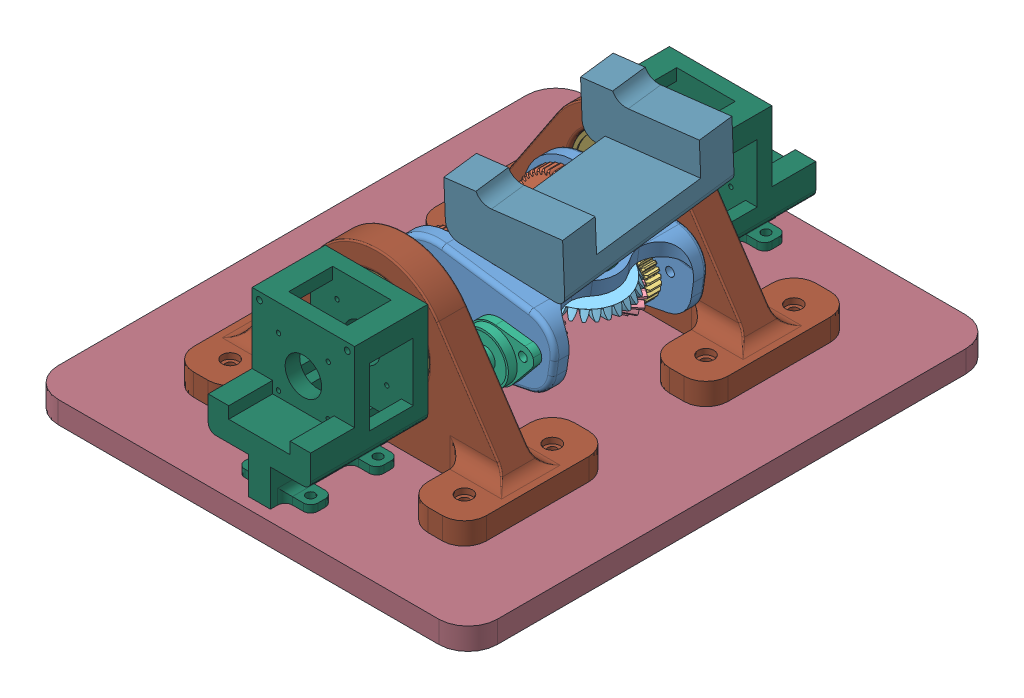
SolidWorks assembly ASSEMBLY Full Design 6th Attempt - Motor Holder, configuration Default. Lengths in mm.
Overall size (300 171.25 360).
32 component instances, 15 part files, 78 mates.
Components (placement in the parent):
- Main Case-1: Main Case [Default] at (-6.6195 108.5231 36.8157) x (0.989686 -0.143255 0) z (0 0 1) size (115 70 185)
- Secondary Big Spur Gear-1: Secondary Big Spur Gear [Default] at (-6.6195 108.5231 51.8157) x (0.357057 0.934082 0) z (0 0 1) size (62.4 62.32 10)
- Secondary Big Spur Gear-2: Secondary Big Spur Gear [Default] at (-6.6195 108.5231 126.8157) x (-0.319318 0.947648 0) z (0 0 1) size (62.4 62.32 10)
- Main Spur Gear - Copy-1: Main Spur Gear - Copy [Default] at (37.9163 102.0767 126.8157) x (-0.43283 0.901476 0) z (0 0 1) size (32.38 32.33 10)
- Main Spur Gear - Copy-2: Main Spur Gear - Copy [Default] at (37.9163 102.0767 51.8157) x (-0.929585 0.368609 0) z (0 0 1) size (32.38 32.33 10)
- Secondary Bevel Gear-1: Secondary Bevel Gear [Default] at (37.9163 102.0767 59.4378) x (0.929585 -0.368609 0) z (-0.368609 -0.929585 0) size (38.4 11.9 38.26)
- Secondary Bevel Gear-2: Secondary Bevel Gear [Default] at (37.9163 102.0767 119.1936) x (-0.43283 0.901476 0) z (-0.901476 -0.43283 0) size (38.4 11.9 38.26)
- Secondary Main Bevel Gear-1: Secondary Main Bevel Gear [Default] at (40.3976 119.2185 89.3157) x (-0.989538 0.143233 -0.017312) z (-0.017134 0.00248 0.99985) size (61.9 10.12 62)
- Main Slewing Bearing-1: Main Slewing Bearing [Default] at (42.9302 136.7157 89.3157) x (0 0 -1) z (0.989686 -0.143255 0) size (60 15.5 36)
- Secondary Gear Shaft-1: Secondary Gear Shaft [Default] at (46.6696 162.5492 89.3157) x (0.989538 -0.143233 0.017312) z (0.017134 -0.00248 -0.99985) size (10 46 10)
- Secondary Gear Shaft Horizontal-1: Secondary Gear Shaft Horizontal [Default] at (37.9163 102.0767 158.285) x (0.43283 -0.901476 0) z (0.901476 0.43283 0) size (10 46 10)
- Secondary Gear Shaft Horizontal-3: Secondary Gear Shaft Horizontal [Default] at (37.9163 102.0767 20.3464) x (-0.929585 0.368609 0) z (0.368609 0.929585 0) size (10 46 10)
- Main Slewing Bearing-2: Main Slewing Bearing [Default] at (37.9163 102.0767 36.8157) x (0.92872 0.370781 0) z (-0.370781 0.92872 0) size (60 15.5 36)
- Main Slewing Bearing-3: Main Slewing Bearing [Default] at (37.9163 102.0767 141.8157) x (0.92872 0.370781 0) z (0.370781 -0.92872 0) size (60 15.5 36)
- Main Bearing-1: Main Bearing [Default] at (-6.6195 108.5231 136.8157) size (25 25 10)
- Main Bearing-2: Main Bearing [Default] at (-6.6195 108.5231 41.8157) size (25 25 10)
- Secondary Gear Shaft Horizontal Back-1: Secondary Gear Shaft Horizontal Back [Default] at (-6.6195 108.5231 -23.1843) x (0.357057 0.934082 0) z (0.934082 -0.357057 0) size (10 80 10)
- Secondary Gear Shaft Horizontal Back-2: Secondary Gear Shaft Horizontal Back [Default] at (-6.6195 108.5231 201.8157) x (0.319318 -0.947648 0) z (0.947648 0.319318 0) size (10 80 10)
- Main Bearing-3: Main Bearing [Default] at (-6.6195 108.5231 176.8157) size (25 25 10)
- Main Bearing-4: Main Bearing [Default] at (-6.6195 108.5231 1.8157) x (0.957621 -0.288033 0) z (0 0 1) size (25 25 10)
- Main Holder-1: Main Holder [Default] at (-6.6195 108.5231 171.8157) size (200 110 100)
- Main Holder-2: Main Holder [Default] at (-6.6195 108.5231 6.8157) size (200 110 100)
- Main Bearing Big-1: Main Bearing Big [Default] at (-6.6195 108.5231 171.8157) size (70 70 15)
- Main Bearing Big-2: Main Bearing Big [Default] at (-6.6195 108.5231 6.8157) size (70 70 15)
- Bottom Plate-1: Bottom Plate [Default] at (-6.6195 33.5231 89.3157) x (0 0 1) z (-1 0 0) size (360 15 300)
- Ham Duong-1: Ham Duong [Default] at (9.1871 201.8442 93.8718) x (-0.9942 -0.025249 0.10454) z (-0.104942 0.01519 -0.994362) size (73.61 54.09 130)
- Main Motor Holder-1: Main Motor Holder [Default] at (-6.6195 108.5231 221.8157) size (70 95 80)
- Main Motor Holder-2: Main Motor Holder [Default] at (-6.6195 108.5231 -43.1843) x (-1 0 0) z (0 0 -1) size (70 95 80)
- Main Bearing-5: Main Bearing [Default] at (-6.6195 108.5231 -8.1843) size (25 25 10)
- Main Bearing-6: Main Bearing [Default] at (-6.6195 108.5231 186.8157) size (25 25 10) (hidden)
- Main Bearing-7: Main Bearing [Default] at (-6.6195 108.5231 226.8157) size (25 25 10) (hidden)
- Main Bearing-8: Main Bearing [Default] at (-6.6195 108.5231 -48.1843) size (25 25 10)
Mates (geometry in assembly coordinates):
- Concentric1: concentric aligned: cylinder of Main Case-1 through (-6.6195 108.5231 131.8157) axis (0 0 1) radius 12.5; cylinder of Secondary Big Spur Gear-2 through (-6.6195 108.5231 121.8157) axis (0 0 1) radius 5
- Coincident1: coincident anti-aligned: plane of Main Case-1 through (-6.6195 108.5231 131.8157) normal (0 0 -1); plane of Secondary Big Spur Gear-2 through (-6.6195 108.5231 131.8157) normal (0 0 1)
- Concentric2: concentric anti-aligned: cylinder of Main Case-1 through (-6.6195 108.5231 46.8157) axis (0 0 -1) radius 12.5; cylinder of Secondary Big Spur Gear-1 through (-6.6195 108.5231 46.8157) axis (0 0 1) radius 5
- Coincident2: coincident anti-aligned: plane of Main Case-1 through (-6.6195 108.5231 46.8157) normal (0 0 1); plane of Secondary Big Spur Gear-1 through (-6.6195 108.5231 46.8157) normal (0 0 -1)
- Concentric3: concentric anti-aligned: cylinder of Main Case-1 through (37.9163 102.0767 46.8157) axis (0 0 -1) radius 5; cylinder of Main Spur Gear - Copy-2 through (37.9163 102.0767 46.8157) axis (0 0 1) radius 5
- Coincident3: coincident anti-aligned: plane of Main Case-1 through (-6.6195 108.5231 46.8157) normal (0 0 1); plane of Main Spur Gear - Copy-2 through (37.9163 102.0767 46.8157) normal (0 0 -1)
- GearMate1: gear = 60 : 30 mm: circle of Main Spur Gear - Copy-2; circle of Secondary Big Spur Gear-1
- Concentric5: concentric aligned: cylinder of Main Case-1 through (37.9163 102.0767 131.8157) axis (0 0 1) radius 5; cylinder of Main Spur Gear - Copy-1 through (37.9163 102.0767 121.8157) axis (0 0 1) radius 5
- Coincident4: coincident anti-aligned: plane of Main Case-1 through (-6.6195 108.5231 131.8157) normal (0 0 -1); plane of Main Spur Gear - Copy-1 through (37.9163 102.0767 131.8157) normal (0 0 1)
- GearMate2: gear = 60 : 30 mm: circle of Main Spur Gear - Copy-1; circle of Secondary Big Spur Gear-2
- Concentric7: concentric aligned: cylinder of Main Case-1 through (37.9163 102.0767 46.8157) axis (0 0 -1) radius 5; cylinder of Secondary Bevel Gear-1 through (37.9163 102.0767 68.8963) axis (0 0 -1) radius 5
- Coincident5: coincident aligned: plane of Main Spur Gear - Copy-2 through (37.1952 94.8324 46.8157) normal (0.368609 0.929585 0); plane of Secondary Bevel Gear-1 through (33.4769 96.3068 68.8963) normal (0.368609 0.929585 0)
- Concentric8: concentric aligned: cylinder of Main Spur Gear - Copy-1 through (37.9163 102.0767 121.8157) axis (0 0 1) radius 5; cylinder of Secondary Bevel Gear-2 through (37.9163 102.0767 109.7351) axis (0 0 1) radius 5
- Coincident6: coincident aligned: plane of Main Spur Gear - Copy-1 through (32.4717 97.2439 121.8157) normal (0.901476 0.43283 0); plane of Secondary Bevel Gear-2 through (32.4717 97.2439 109.7351) normal (0.901476 0.43283 0)
- Concentric9: concentric aligned: cylinder of Main Case-1 through (32.9024 67.4377 89.3157) axis (0.143255 0.989686 0) radius 5; cylinder of Secondary Main Bevel Gear-1 through (39.5059 113.0582 89.3157) axis (0.143255 0.989686 0) radius 5
- Coincident7: coincident: point of Secondary Bevel Gear-1; point of Secondary Main Bevel Gear-1
- Coincident8: coincident: line of Secondary Bevel Gear-2 through (37.9163 102.0767 89.3157) axis (0.216415 -0.450738 0.866025)
- GearMate3: gear = 34.5 : 60 mm: circle of Secondary Main Bevel Gear-1; circle of Secondary Bevel Gear-1
- GearMate4: gear = 60 : 34.5 mm: circle of Secondary Bevel Gear-2; circle of Secondary Main Bevel Gear-1
- Concentric11: concentric aligned: cylinder of Main Case-1 through (32.9024 67.4377 89.3157) axis (0.143255 0.989686 0) radius 5; cylinder of Main Slewing Bearing-1 through (42.9302 136.7157 89.3157) axis (0.143255 0.989686 0) radius 5
- Concentric12: concentric anti-aligned: cylinder of Main Case-1 through (42.9302 136.7157 66.8157) axis (0.143255 0.989686 0) radius 3; cylinder of Main Slewing Bearing-1 through (43.7181 142.1589 66.8157) axis (-0.143255 -0.989686 0) radius 3
- Coincident9: coincident anti-aligned: plane of Main Case-1 through (-1.6056 143.1621 46.8157) normal (0.143255 0.989686 0); plane of Main Slewing Bearing-1 through (42.9302 136.7157 89.3157) normal (-0.143255 -0.989686 0)
- Concentric13: concentric aligned: cylinder of Main Slewing Bearing-1 through (42.9302 136.7157 89.3157) axis (0.143255 0.989686 0) radius 5; cylinder of Secondary Gear Shaft-1 through (40.0799 117.0237 89.3157) axis (0.143255 0.989686 0) radius 5
- Coincident10: coincident aligned: plane of Secondary Main Bevel Gear-1 through (59.6258 114.1945 89.6577) normal (-0.143255 -0.989686 0); plane of Secondary Gear Shaft-1 through (40.0799 117.0237 89.3157) normal (-0.143255 -0.989686 0)
- Coincident11: coincident aligned: plane of Secondary Main Bevel Gear-1 through (41.4064 112.7831 93.9322) normal (-0.989538 0.143233 -0.017312); plane of Secondary Gear Shaft-1 through (43.4401 126.6415 92.3499) normal (-0.989538 0.143233 -0.017312)
- Concentric14: concentric aligned: cylinder of Secondary Bevel Gear-1 through (37.9163 102.0767 68.8963) axis (0 0 -1) radius 5; cylinder of Secondary Gear Shaft Horizontal-3 through (37.9163 102.0767 66.3464) axis (0 0 -1) radius 5
- Coincident12: coincident aligned: plane of Secondary Bevel Gear-1 through (29.3082 105.4901 66.3464) normal (0 0 1); plane of Secondary Gear Shaft Horizontal-3 through (37.9163 102.0767 66.3464) normal (0 0 1)
- Coincident15: coincident aligned: plane of Secondary Bevel Gear-1 through (34.368 98.554 68.8963) normal (0.929585 -0.368609 0); plane of Secondary Gear Shaft Horizontal-3 through (34.9513 100.0251 56.3464) normal (0.929585 -0.368609 0)
- Concentric15: concentric aligned: cylinder of Secondary Bevel Gear-2 through (37.9163 102.0767 109.7351) axis (0 0 1) radius 5; cylinder of Secondary Gear Shaft Horizontal-1 through (37.9163 102.0767 112.285) axis (0 0 1) radius 5
- Coincident16: coincident aligned: plane of Secondary Bevel Gear-2 through (41.9244 93.7288 112.285) normal (0 0 -1); plane of Secondary Gear Shaft Horizontal-1 through (37.9163 102.0767 112.285) normal (0 0 -1)
- Coincident17: coincident aligned: plane of Secondary Bevel Gear-2 through (34.6509 98.2902 109.7351) normal (-0.43283 0.901476 0); plane of Secondary Gear Shaft Horizontal-1 through (36.0776 98.9752 122.285) normal (-0.43283 0.901476 0)
- Concentric16: concentric aligned: cylinder of Secondary Gear Shaft Horizontal-3 through (37.9163 102.0767 66.3464) axis (0 0 -1) radius 5; cylinder of Main Slewing Bearing-2 through (37.9163 102.0767 36.8157) axis (0 0 -1) radius 5
- Coincident18: coincident anti-aligned: plane of Main Case-1 through (-6.6195 108.5231 36.8157) normal (0 0 -1); plane of Main Slewing Bearing-2 through (37.9163 102.0767 36.8157) normal (0 0 1)
- Concentric17: concentric anti-aligned: cylinder of Main Case-1 through (58.8125 110.4192 141.8157) axis (0 0 -1) radius 3; cylinder of Main Slewing Bearing-2 through (58.8125 110.4192 31.3157) axis (0 0 1) radius 3
- Concentric18: concentric aligned: cylinder of Secondary Gear Shaft Horizontal-1 through (37.9163 102.0767 112.285) axis (0 0 1) radius 5; cylinder of Main Slewing Bearing-3 through (37.9163 102.0767 141.8157) axis (0 0 1) radius 5
- Concentric19: concentric aligned: cylinder of Main Case-1 through (58.8125 110.4192 141.8157) axis (0 0 -1) radius 3; cylinder of Main Slewing Bearing-3 through (58.8125 110.4192 147.3157) axis (0 0 -1) radius 3
- Coincident19: coincident anti-aligned: plane of Main Case-1 through (-6.6195 108.5231 141.8157) normal (0 0 1); plane of Main Slewing Bearing-3 through (37.9163 102.0767 141.8157) normal (0 0 -1)
- Concentric20: concentric anti-aligned: cylinder of Main Case-1 through (-6.6195 108.5231 131.8157) axis (0 0 1) radius 12.5; cylinder of Main Bearing-1 through (-6.6195 108.5231 141.8157) axis (0 0 -1) radius 12.5
- Coincident20: coincident aligned: plane of Main Case-1 through (-6.6195 108.5231 141.8157) normal (0 0 1); plane of Main Bearing-1 through (-6.6195 108.5231 141.8157) normal (0 0 1)
- Concentric21: concentric aligned: cylinder of Main Case-1 through (-6.6195 108.5231 46.8157) axis (0 0 -1) radius 12.5; cylinder of Main Bearing-2 through (-6.6195 108.5231 46.8157) axis (0 0 -1) radius 5
- Coincident21: coincident aligned: plane of Main Case-1 through (-6.6195 108.5231 36.8157) normal (0 0 -1); plane of Main Bearing-2 through (-6.6195 108.5231 36.8157) normal (0 0 -1)
- Concentric22: concentric aligned: cylinder of Main Bearing-2 through (-6.6195 108.5231 46.8157) axis (0 0 -1) radius 5; cylinder of Secondary Gear Shaft Horizontal Back-1 through (-6.6195 108.5231 56.8157) axis (0 0 -1) radius 5
- Coincident22: coincident aligned: plane of Secondary Big Spur Gear-1 through (-6.6195 108.5231 56.8157) normal (0 0 1); plane of Secondary Gear Shaft Horizontal Back-1 through (-6.6195 108.5231 56.8157) normal (0 0 1)
- Coincident23: coincident aligned: plane of Secondary Big Spur Gear-1 through (-11.6141 108.2912 46.8157) normal (0.357057 0.934082 0); plane of Secondary Gear Shaft Horizontal Back-1 through (-10.1359 107.7261 46.8157) normal (0.357057 0.934082 0)
- Concentric23: concentric anti-aligned: cylinder of Main Bearing-1 through (-6.6195 108.5231 141.8157) axis (0 0 -1) radius 5; cylinder of Secondary Gear Shaft Horizontal Back-2 through (-6.6195 108.5231 121.8157) axis (0 0 1) radius 5
- Coincident24: coincident aligned: plane of Secondary Big Spur Gear-2 through (-6.6195 108.5231 121.8157) normal (0 0 -1); plane of Secondary Gear Shaft Horizontal Back-2 through (-6.6195 108.5231 121.8157) normal (0 0 -1)
- Coincident25: coincident aligned: plane of Secondary Big Spur Gear-2 through (-10.3236 105.1645 121.8157) normal (-0.319318 0.947648 0); plane of Secondary Gear Shaft Horizontal Back-2 through (-8.8238 105.6699 131.8157) normal (-0.319318 0.947648 0)
- Concentric24: concentric anti-aligned: cylinder of Main Case-1 through (-6.6195 108.5231 131.8157) axis (0 0 1) radius 12.5; cylinder of Main Bearing-3 through (-6.6195 108.5231 181.8157) axis (0 0 -1) radius 12.5
- Coincident26: coincident aligned: plane of Main Case-1 through (-6.6195 108.5231 181.8157) normal (0 0 1); plane of Main Bearing-3 through (-6.6195 108.5231 181.8157) normal (0 0 1)
- Concentric25: concentric aligned: cylinder of Main Case-1 through (-6.6195 108.5231 46.8157) axis (0 0 -1) radius 12.5; cylinder of Main Bearing-4 through (-6.6195 108.5231 6.8157) axis (0 0 -1) radius 12.5
- Coincident27: coincident aligned: plane of Main Case-1 through (-6.6195 108.5231 -3.1843) normal (0 0 -1); plane of Main Bearing-4 through (-6.6195 108.5231 -3.1843) normal (0 0 -1)
- Concentric26: concentric aligned: cylinder of Main Holder-1 through (-6.6195 108.5231 221.8157) axis (0 0 -1) radius 35; cylinder of Main Bearing Big-1 through (-6.6195 108.5231 179.3157) axis (0 0 -1) radius 35
- Coincident28: coincident aligned: plane of Main Holder-1 through (-6.6195 108.5231 171.8157) normal (0 0 1); plane of Main Bearing Big-1 through (-6.6195 108.5231 171.8157) normal (0 0 1)
- Coincident29: coincident aligned: plane of Main Holder-2 through (-6.6195 108.5231 6.8157) normal (0 0 1); plane of Main Bearing Big-2 through (-6.6195 108.5231 6.8157) normal (0 0 1)
- Concentric27: concentric aligned: cylinder of Main Holder-2 through (-6.6195 108.5231 56.8157) axis (0 0 -1) radius 35; cylinder of Main Bearing Big-2 through (-6.6195 108.5231 14.3157) axis (0 0 -1) radius 35
- Concentric28: concentric aligned: cylinder of Main Case-1 through (-6.6195 108.5231 181.8157) axis (0 0 -1) radius 20; cylinder of Main Bearing Big-1 through (-6.6195 108.5231 179.3157) axis (0 0 -1) radius 20
- Concentric29: concentric anti-aligned: cylinder of Main Case-1 through (-6.6195 108.5231 -3.1843) axis (0 0 1) radius 20; cylinder of Main Bearing Big-2 through (-6.6195 108.5231 14.3157) axis (0 0 -1) radius 20
- Coincident30: coincident aligned: plane of Main Case-1 through (-6.6195 108.5231 181.8157) normal (0 0 1); plane of Main Holder-1 through (-6.6195 108.5231 181.8157) normal (0 0 1)
- Coincident31: coincident aligned: plane of Main Case-1 through (-6.6195 108.5231 -3.1843) normal (0 0 -1); plane of Main Holder-2 through (-6.6195 108.5231 -3.1843) normal (0 0 -1)
- Coincident32: coincident anti-aligned: plane of Main Holder-2 through (-106.6195 48.5231 16.8157) normal (0 -1 0); plane of Bottom Plate-1 through (-6.6195 48.5231 89.3157) normal (0 1 0)
- Concentric33: concentric aligned: cylinder of Secondary Gear Shaft-1 through (40.0799 117.0237 89.3157) axis (0.143255 0.989686 0) radius 5; cylinder of Ham Duong-1 through (44.9505 150.673 89.3157) axis (0.143255 0.989686 0) radius 5
- Coincident33: coincident anti-aligned: plane of Secondary Gear Shaft-1 through (46.6696 162.5492 89.3157) normal (0.143255 0.989686 0); plane of Ham Duong-1 through (70.8182 159.0538 21.3452) normal (-0.143255 -0.989686 0)
- Concentric34: concentric anti-aligned: cylinder of Secondary Gear Shaft Horizontal Back-2 through (-6.6195 108.5231 121.8157) axis (0 0 1) radius 5; cylinder of Main Motor Holder-1 through (-6.6195 108.5231 231.8157) axis (0 0 -1) radius 12.5
- Coincident34: coincident anti-aligned: plane of Main Holder-1 through (-6.6195 108.5231 181.8157) normal (0 0 1); plane of Main Motor Holder-1 through (-6.6195 108.5231 181.8157) normal (0 0 -1)
- Coincident35: coincident anti-aligned: plane of Bottom Plate-1 through (-6.6195 48.5231 89.3157) normal (0 1 0); plane of Main Motor Holder-1 through (-6.6195 48.5231 221.8157) normal (0 -1 0)
- Coincident36: coincident anti-aligned: plane of Bottom Plate-1 through (-6.6195 48.5231 89.3157) normal (0 1 0); plane of Main Motor Holder-2 through (-6.6195 48.5231 -43.1843) normal (0 -1 0)
- Coincident37: coincident anti-aligned: plane of Main Holder-2 through (-6.6195 108.5231 -3.1843) normal (0 0 -1); plane of Main Motor Holder-2 through (-6.6195 108.5231 -3.1843) normal (0 0 1)
- Concentric35: concentric anti-aligned: cylinder of Secondary Gear Shaft Horizontal Back-1 through (-6.6195 108.5231 56.8157) axis (0 0 -1) radius 5; cylinder of Main Motor Holder-2 through (-6.6195 108.5231 -53.1843) axis (0 0 1) radius 12.5
- Concentric37: concentric aligned: cylinder of Secondary Gear Shaft Horizontal Back-1 through (-6.6195 108.5231 56.8157) axis (0 0 -1) radius 5; cylinder of Main Bearing-5 through (-6.6195 108.5231 -3.1843) axis (0 0 -1) radius 12.5
- Coincident38: coincident aligned: plane of Main Motor Holder-2 through (-6.6195 108.5231 -13.1843) normal (0 0 -1); plane of Main Bearing-5 through (-6.6195 108.5231 -13.1843) normal (0 0 -1)
- Concentric39: concentric anti-aligned: cylinder of Main Motor Holder-2 through (-6.6195 108.5231 -53.1843) axis (0 0 1) radius 12.5; cylinder of Main Bearing-8 through (-6.6195 108.5231 -43.1843) axis (0 0 -1) radius 12.5
- Coincident39: coincident aligned: plane of Main Motor Holder-2 through (-6.6195 108.5231 -53.1843) normal (0 0 -1); plane of Main Bearing-8 through (-6.6195 108.5231 -53.1843) normal (0 0 -1)
- Concentric40: concentric anti-aligned: cylinder of Main Motor Holder-1 through (-6.6195 108.5231 181.8157) axis (0 0 1) radius 12.5; cylinder of Main Bearing-6 through (-6.6195 108.5231 191.8157) axis (0 0 -1) radius 12.5
- Coincident40: coincident aligned: plane of Main Motor Holder-1 through (-6.6195 108.5231 191.8157) normal (0 0 1); plane of Main Bearing-6 through (-6.6195 108.5231 191.8157) normal (0 0 1)
- Concentric41: concentric aligned: cylinder of Main Motor Holder-1 through (-6.6195 108.5231 231.8157) axis (0 0 -1) radius 12.5; cylinder of Main Bearing-7 through (-6.6195 108.5231 231.8157) axis (0 0 -1) radius 5
- Coincident41: coincident aligned: plane of Main Motor Holder-1 through (-6.6195 108.5231 231.8157) normal (0 0 1); plane of Main Bearing-7 through (-6.6195 108.5231 231.8157) normal (0 0 1)
- Concentric42: concentric aligned: cylinder of Main Holder-2 through (73.3805 63.5231 -23.1843) axis (0 1 0) radius 3.2; cylinder of Bottom Plate-1 through (73.3805 48.5231 -23.1843) axis (0 1 0) radius 3
- Concentric43: concentric aligned: circle of Main Holder-1; cylinder of Bottom Plate-1 through (-86.6195 48.5231 201.8157) axis (0 1 0) radius 3
